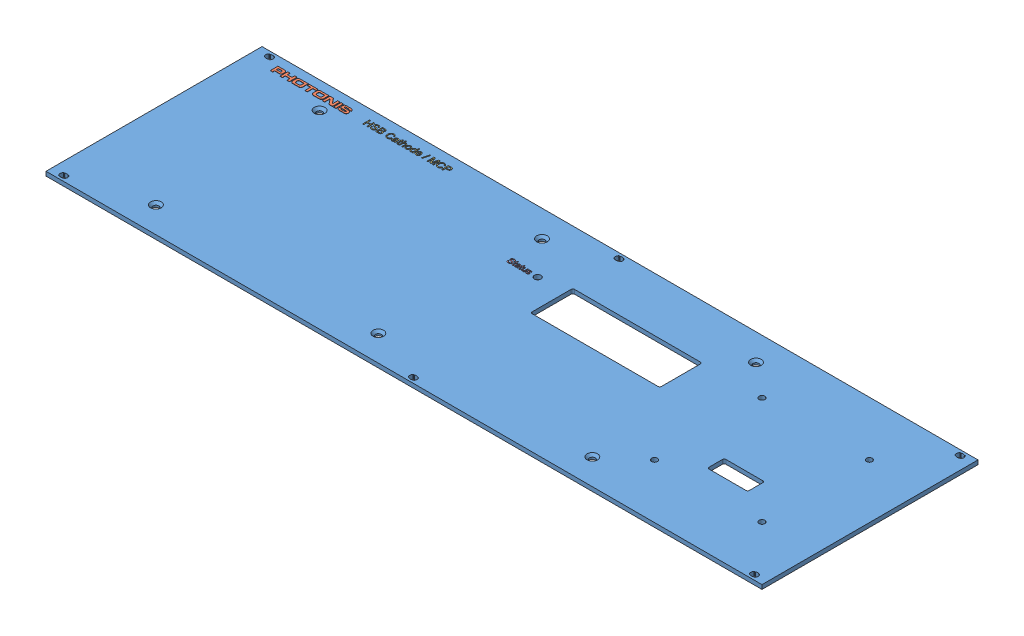
SolidWorks assembly MLA-0387-M11, configuration Default. Lengths in mm.
Overall size (426.52 2.65 128.7).
4 component instances, 4 part files, 9 mates.
Components (placement in the parent):
- MLA-0387-M1-1: MLA-0387-M1 [Default] at (-7.8975 -174.6729 597.0963) size (426.52 2.5 128.7)
- LOGO PHOTONIS-1: LOGO PHOTONIS [Default] at (9.7425 205.5771 259.7963) x (1 0 0) z (0 1 0) size (45.16 4.45 0.15)
- Kathode-MCP text-1: Kathode-MCP text [Default] at (64.2855 205.4271 259.8791) size (50 0.1 4.1)
- Status text-1: Status text [Default] at (178.1079 205.4271 288.0463) size (13.33 0.1 3.59)
Mates (geometry in assembly coordinates):
- Coincident1: coincident anti-aligned: plane of MLA-0387-M1-1 through (0.1829 205.4271 294.0204) normal (0 1 0); plane of LOGO PHOTONIS-1 through (13.9262 205.4271 256.4739) normal (0 -1 0)
- Distance1: distance = 15 mm aligned: plane of LOGO PHOTONIS-1 through (9.7425 205.4271 259.7963) normal (-1 0 0); plane of MLA-0387-M1-1 through (-5.2575 202.9271 334.0463) normal (-1 0 0)
- Distance2: distance = 10 mm anti-aligned: plane of LOGO PHOTONIS-1 through (11.1035 205.4271 259.7963) normal (0 0 1); plane of MLA-0387-M1-1 through (-5.2575 202.9271 249.7963) normal (0 0 -1)
- Coincident4: coincident anti-aligned: plane of MLA-0387-M1-1 through (0.1829 205.4271 294.0204) normal (0 1 0); plane of Kathode-MCP text-1 through (64.2855 205.4271 259.8791) normal (0 -1 0)
- Distance3: distance = 10 mm anti-aligned: plane of Kathode-MCP text-1 through (65.3066 205.5271 259.7963) normal (0 0 1); plane of MLA-0387-M1-1 through (-5.2575 202.9271 249.7963) normal (0 0 -1)
- Distance4: distance = 70 mm aligned: plane of Kathode-MCP text-1 through (64.7425 205.5271 259.7963) normal (-1 0 0); plane of MLA-0387-M1-1 through (-5.2575 202.9271 334.0463) normal (-1 0 0)
- Coincident7: coincident anti-aligned: plane of MLA-0387-M1-1 through (0.1829 205.4271 294.0204) normal (0 1 0); plane of Status text-1 through (178.7733 205.4271 287.7934) normal (0 -1 0)
- Distance5: distance = 38.25 mm anti-aligned: plane of Status text-1 through (189.1015 205.5271 288.0463) normal (0 0 1); plane of MLA-0387-M1-1 through (-5.2575 202.9271 249.7963) normal (0 0 -1)
- Distance6: distance = 187 mm: plane of Status text-1 through (181.7425 205.5271 287.3277) normal (-1 0 0); line of MLA-0387-M1-1 through (-5.2575 205.4271 378.4963) axis (0 0 -1)
